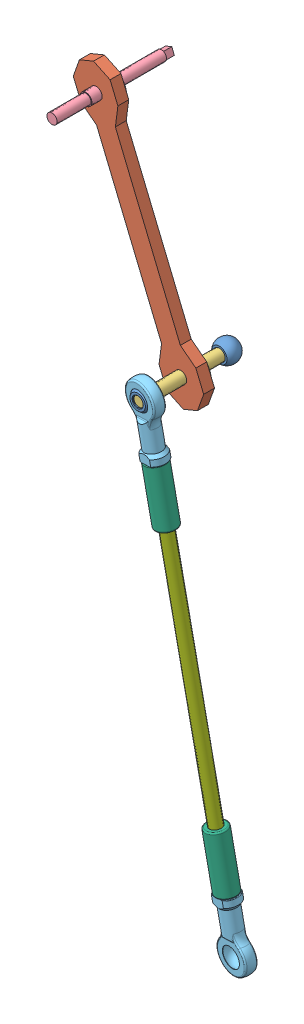
SolidWorks assembly Ensamblaje4, configuration Predeterminado. Lengths in mm.
Overall size (117.73 421.99 71.93).
12 component instances, 7 part files, 1 mates.
Components (placement in the parent):
- BrazoCompleto-1: BrazoCompleto [Predeterminado] at (-6.2436 -54.2938 156.7981) size (83 156.8 69.5)
  - ball_for_PHSA6-1: ball_for_PHSA6 [По умолчанию] at (-1.4886 1.4494 12.8) size (12.8 12.8 9)
  - ball_for_PHSA6-2: ball_for_PHSA6 [По умолчанию] at (-1.4886 1.4494 -35.3) x (-0.923728 -0.383049 0) z (0 0 -1) size (12.8 12.8 9)
  - Brazo-1: Brazo [Predeterminado] at (-20.5839 47.498 -8.05) x (-0.923728 -0.383049 0) z (0 0 -1) size (23.5 160 6.4)
  - Acople-Brazo-RUniball-1: Acople-Brazo-RUniball [Predeterminado] at (-1.4886 1.4494 16.5) x (-0.923728 -0.383049 0) z (0 0 -1) size (19 19 55.5)
  - Eje-Base-Brazo-1: Eje-Base-Brazo [Predeterminado] at (-51.2849 121.534 18) x (-0.923728 -0.383049 0) z (0 0 -1) size (19 19 69.5)
- AntebrazoCompleto-1: AntebrazoCompleto [Predeterminado] at (-44.3827 -68.8989 148.4203) x (0.104182 0.068798 -0.992176) z (0.984226 0.136293 0.112798) size (12 295.2 20.2)
  - PHSA6-1: PHSA6 [По умолчанию] at (-16.0893 11.759 40.6494) size (10.8 40.65 20.2)
  - PHSA6-2: PHSA6 [По умолчанию] at (-16.0893 -263.241 40.6494) x (-1 0 0) z (0 0 1) size (10.8 40.65 20.2)
  - Acople-Antebrazo-RUniball-1: Acople-Antebrazo-RUniball [Predeterminado] at (-16.0893 -51.741 40.6494) x (1 0 0) z (0 1 0) size (12 12 53)
  - Acople-Antebrazo-RUniball-2: Acople-Antebrazo-RUniball [Predeterminado] at (-16.0893 -199.741 40.6494) x (1 0 0) z (0 -1 0) size (12 12 53)
  - Antebrazo-1: Antebrazo [Predeterminado] at (-16.0893 -23.741 40.6494) x (1 0 0) z (0 -1 0) size (7 7 204)
Mates (geometry in assembly coordinates):
- Concéntrica1: concentric: sphere of BrazoCompleto-1/ball_for_PHSA6-1; sphere of AntebrazoCompleto-1/PHSA6-1
